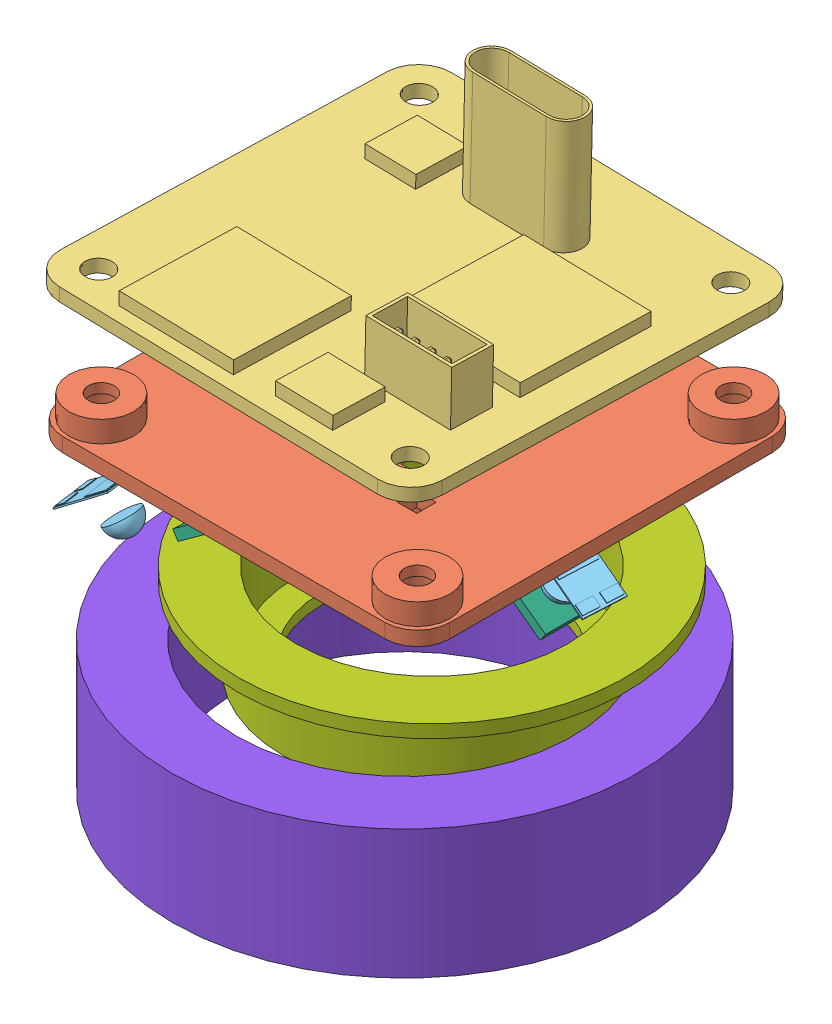
SolidWorks assembly tryassem - Copy, configuration Default. Lengths in mm.
Overall size (36 42.77 36).
12 component instances, 9 part files, 0 mates.
Components (placement in the parent):
- Absorption Filter 02-1: Absorption Filter 02 [Default] at (1.5634 -2.8478 -2.3822) size (7.5 0.82 7)
- Assem2-1: Assem2 [Default] at (1.5822 -0.426 -2.0394) size (30 9.55 30)
  - foursideillum_wire_45degree_090922-1: foursideillum_wire_45degree_090922 [Default] at origin size (30 9.55 30)
- DMM 37UX178-ML.ipt-1: DMM 37UX178-ML.ipt [Default] at (1.4971 9.1076 -1.9169) x (0.99986 -0.008821 0.014185) z (0.014059 -0.014216 -0.9998) size (30 11.76 30)
- Dielectric Filter 02.ipt-1: Dielectric Filter 02.ipt [Default] at (1.5716 -4.78 -2.0284) size (7.5 0.81 7)
- LED-1: LED [Default] at (13.3191 -4.8518 -2.581) x (0.84653 -0.528912 0.060332) z (-0.100415 -0.047354 0.993818) size (4.61 3.35 3.17)
- LED-2: LED [Default] at (-8.7647 -3.2277 11.8808) x (-0.803558 -0.585072 0.109479) z (-0.137047 0.002871 -0.99056) size (4.61 3.35 3.17)
- filter1-1: filter1 [Default] at (9.9042 -8.82 -3.3682) x (0.014364 0.009768 -0.999849) z (0.812145 -0.583425 0.005968) size (3.5 0.75 3)
- filter1-2: filter1 [Default] at (-7.7957 -8.0862 5.1341) x (-0.04426 0.02412 0.998729) z (0.807439 0.589557 0.021545) size (3.5 0.75 3)
- Chamber_interts_modified-1: Chamber_interts_modified [Default] at (1.7526 -13.9333 -2.9876) size (30 7 30)
- Cortex_Chamber-1: Cortex_Chamber [Default] at (1.8911 -20.7904 -0.742) size (36 10 36)
- PhaseMask_sldprt-1: PhaseMask_sldprt [Default] at (1.6364 3.9323 -2.4086) x (0.999736 0.004383 -0.022553) z (0.022299 0.051244 0.998437) size (7 0.7 7)
